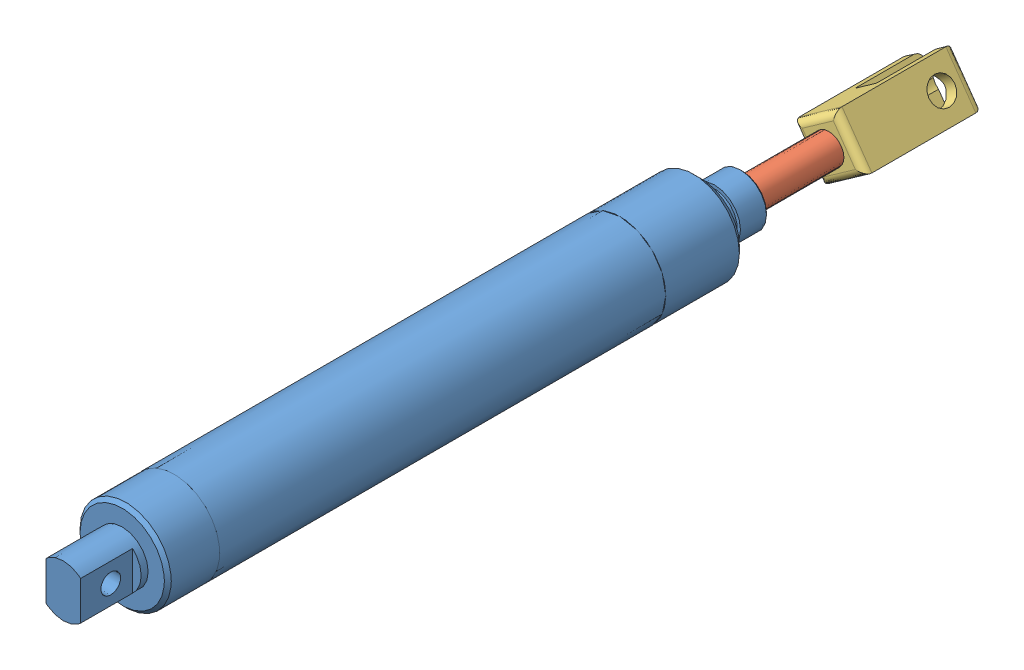
SolidWorks assembly AirCylinder_1.25x5in_Assem, configuration Default. Lengths in mm.
Overall size (33.46 33.46 323.9).
3 component instances, 3 part files, 4 mates.
Components (placement in the parent):
- AirCylinder_1.25x5in-1: AirCylinder_1.25x5in [Default] at origin size (33.46 33.46 248.97)
- AirCylinder_1.25x5in_Rod-1: AirCylinder_1.25x5in_Rod [Default] at (0 0 82.2452) x (-0.267111 0.963666 0) z (0 0 -1) size (11.07 11.07 177.8)
- AirCylinder_Clevas-1: AirCylinder_Clevas [Default] at (2.2933 13.2737 -76.5048) x (0.576401 -0.817167 0) z (0 0 -1) size (19.05 19.05 43.18)
Mates (geometry in assembly coordinates):
- Concentric1: concentric aligned: cylinder of AirCylinder_1.25x5in-1 through (0 0 -29.5148) axis (0 0 1) radius 5.588; cylinder of AirCylinder_1.25x5in_Rod-1 through (0 0 -76.5048) axis (0 0 1) radius 5.5372
- LimitDistance1: limit distance = 127 mm anti-aligned: plane of AirCylinder_1.25x5in_Rod-1 through (0 0 82.2452) normal (0 0 1); plane of AirCylinder_1.25x5in-1 through (-5.588 0 -44.7548) normal (0 0 -1)
- Concentric2: concentric aligned: cylinder of AirCylinder_1.25x5in_Rod-1 through (0 0 -95.5548) axis (0 0 1) radius 5.5372; cylinder of AirCylinder_Clevas-1 through (0 0 -119.6858) axis (0 0 1) radius 5.08
- Coincident1: coincident anti-aligned: circle of AirCylinder_1.25x5in_Rod-1; plane of AirCylinder_Clevas-1 through (2.2933 13.2737 -76.5048) normal (0 0 1)
